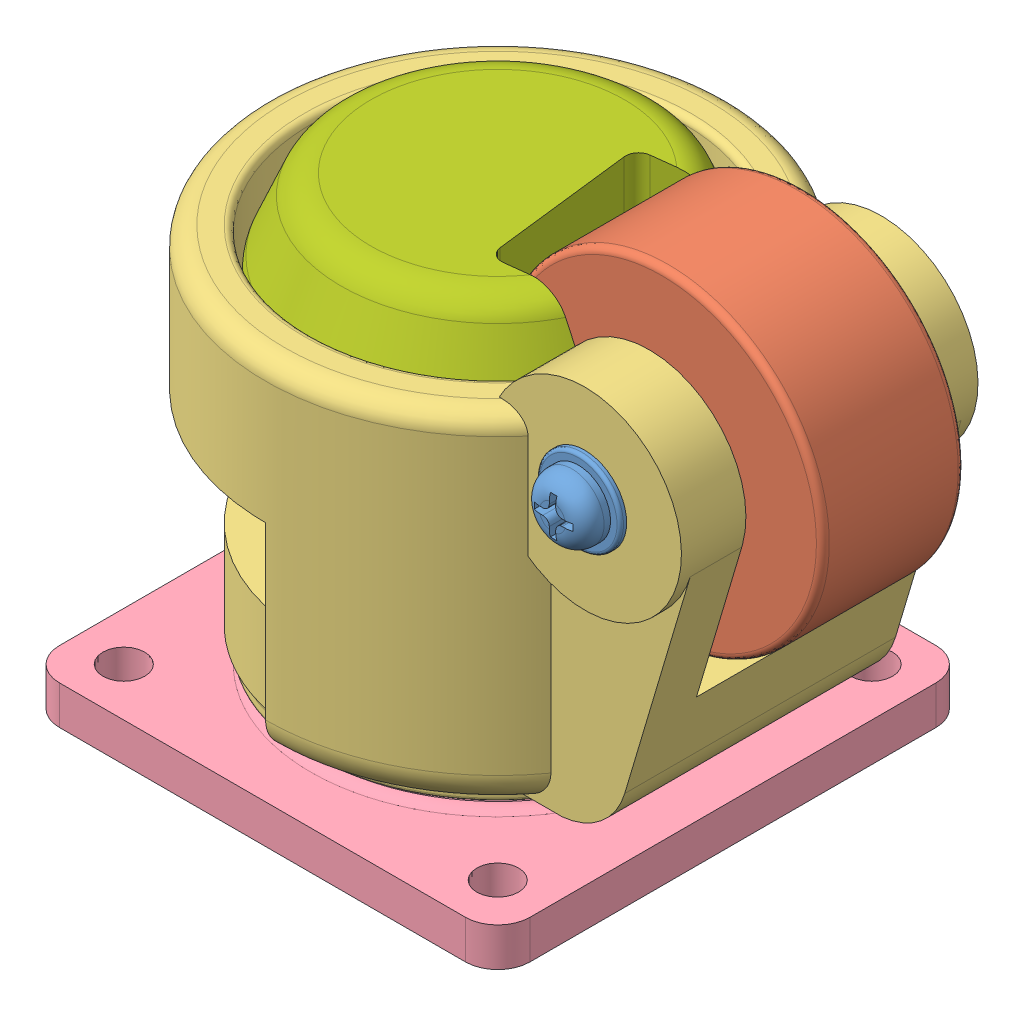
SolidWorks assembly Колесо в сборе, configuration По умолчанию. Lengths in mm.
Overall size (98.3 83.3 73).
7 component instances, 7 part files, 9 mates.
Components (placement in the parent):
- Винт-1: Винт [По умолчанию] at (-105.4178 12.1925 95.7349) size (13 13 56.01)
- Колесо-1: Колесо [По умолчанию] at (-104.7206 11.4146 95.8086) x (0.999929 0.011939 0) z (0 0 1) size (50 50 22)
- Корпус-1: Корпус [По умолчанию] at (-105.4178 12.1925 95.7349) size (87.5 65 72)
- Кронштейн-1: Кронштейн [По умолчанию] at (-105.4178 12.1925 95.7349) size (73 8 73)
- Регулятор-1: Регулятор [По умолчанию] at (-105.4178 12.1925 95.7349) size (51.81 8.11 50)
- Стержень резьбовой-1: Стержень резьбовой [По умолчанию] at (-76.4178 15.444 66.7349) size (10.27 40.63 10.02)
- Пятка-2: Пятка [По умолчанию] at (-101.7957 12.1925 98.9524) x (0.993023 0 -0.117923) z (0.117923 0 0.993023) size (54.2 29 56.01)
Mates (geometry in assembly coordinates):
- Концентричный1: concentric anti-aligned: cylinder of Корпус-1 through (-76.4178 31.1925 66.7349) axis (0 -1 0) radius 7.25; circle of Стержень резьбовой-1
- Концентричный2: concentric aligned: circle of Корпус-1; circle of Регулятор-1
- Совпадение1: coincident anti-aligned: plane of Корпус-1 through (-58.4178 37.1925 96.7349) normal (0 1 0); plane of Регулятор-1 through (-103.2317 37.1925 105.7349) normal (0 -1 0)
- Концентричный3: concentric aligned: circle of Колесо-1; circle of Корпус-1
- Совпадение2: coincident anti-aligned: plane of Винт-1 through (-39.9178 70.1925 43.7349) normal (0 0 1); plane of Корпус-1 through (-39.9178 70.1925 43.7349) normal (0 0 -1)
- Концентричный4: concentric aligned: circle of Винт-1; circle of Корпус-1
- Совпадение3: coincident anti-aligned: circle of Корпус-1; circle of Кронштейн-1
- Концентричный5: concentric: circle of Корпус-1; circle of Пятка-2
- Совпадение4: coincident aligned: plane of Корпус-1 through (-76.4178 55.1925 66.7349) normal (0 -1 0); plane of Пятка-2 through (-62.0811 55.1925 34.8216) normal (0 -1 0)
